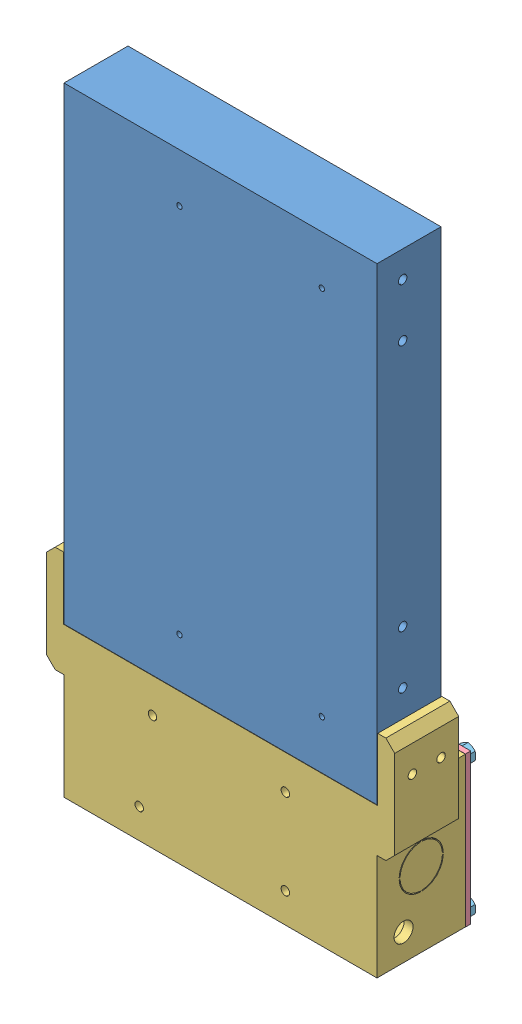
SolidWorks assembly Main, configuration Default. Lengths in mm.
Overall size (200.8 349.9 56.8).
15 component instances, 6 part files, 33 mates.
Components (placement in the parent):
- Box-1: Box [Default] at (0 389.0123 0) x (-1 0 0) z (0 0 -1) size (177 265 36.2)
- Screen Assembly-2: Screen Assembly [Default] at (0 389.0123 -35.1) x (-1 0 0) z (0 0 -1) size (167 255 31.2)
- Box - CTU Addon-1: Box - CTU Addon [Default] at (0 214.2123 0) x (-1 0 0) z (0 0 -1) size (197 120 50)
- Box - Ctu Addon - LID-1: Box - Ctu Addon - LID [Default] at (0 214.0123 -53) x (-1 0 0) z (0 1 0) size (177 3 84.8)
- hex screw_am-2: hex screw_am [B18.6.7M - M5 x 0.8 x 6 Indented HHMS --6N] at (-102.3 271.5123 -26.2) size (9.8 9.24 8)
- hex screw_am-3: hex screw_am [B18.6.7M - M5 x 0.8 x 6 Indented HHMS --6N] at (-102.3 271.5123 -10) size (9.8 9.24 8)
- hex screw_am-4: hex screw_am [B18.6.7M - M5 x 0.8 x 6 Indented HHMS --6N] at (-92.3 306.5123 -14.5) size (9.8 9.24 8)
- hex screw_am-5: hex screw_am [B18.6.7M - M5 x 0.8 x 6 Indented HHMS --6N] at (-92.3 336.5123 -14.5) size (9.8 9.24 8)
- hex screw_am-6: hex screw_am [B18.6.7M - M5 x 0.8 x 6 Indented HHMS --6N] at (-92.3 476.5123 -14.5) size (9.8 9.24 8)
- hex screw_am-7: hex screw_am [B18.6.7M - M5 x 0.8 x 6 Indented HHMS --6N] at (-92.3 506.5123 -14.5) size (9.8 9.24 8)
- hex screw_am-8: hex screw_am [B18.6.7M - M5 x 0.8 x 6 Indented HHMS --6N] at (-83.5 251.7123 -56.8) x (0 0 1) z (-1 0 0) size (9.8 9.24 8)
- hex screw_am-9: hex screw_am [B18.6.7M - M5 x 0.8 x 6 Indented HHMS --6N] at (-83.5 176.7123 -56.8) x (0 0 1) z (-1 0 0) size (9.8 9.24 8)
- hex screw_am-10: hex screw_am [B18.6.7M - M5 x 0.8 x 6 Indented HHMS --6N] at (83.5 176.7123 -56.8) x (0 0 1) z (-1 0 0) size (9.8 9.24 8)
- hex screw_am-11: hex screw_am [B18.6.7M - M5 x 0.8 x 6 Indented HHMS --6N] at (83.5 251.7123 -56.8) x (0 0 1) z (-1 0 0) size (9.8 9.24 8)
- ArduinoMega-1: ArduinoMega [Default] at (0 212.6417 -9.651) size (107.95 53.42 12.95)
Mates (geometry in assembly coordinates):
- Coincident2: coincident anti-aligned: plane of Box-1 through (0 389.0123 -5) normal (0 0 -1); plane of Screen Assembly-2 through (-76.67 509.6823 -5) normal (0 0 1)
- Width1: width aligned: plane of Box-1 through (83.7 261.3123 -36.2) normal (0 1 0); plane of Box-1 through (-83.7 516.7123 -36.2) normal (0 -1 0); plane of Screen Assembly-2 through (76.67 516.5123 -36.2) normal (0 1 0); plane of Screen Assembly-2 through (76.67 261.5123 -36.2) normal (0 -1 0)
- Width2: width anti-aligned: plane of Screen Assembly-2 through (-83.5 268.3423 -36.2) normal (-1 0 0); plane of Screen Assembly-2 through (83.5 268.3423 -36.2) normal (1 0 0); plane of Box-1 through (-83.7 261.3123 -36.2) normal (1 0 0); plane of Box-1 through (83.7 516.7123 -36.2) normal (-1 0 0)
- Width3: width aligned: plane of Box-1 through (-88.5 256.5123 -5) normal (-1 0 0); plane of Box-1 through (88.5 256.5123 -5) normal (1 0 0); plane of Box - CTU Addon-1 through (-88.5 171.7123 -50) normal (-1 0 0); plane of Box - CTU Addon-1 through (88.5 171.7123 -50) normal (1 0 0)
- Coincident4: coincident aligned: plane of Box-1 through (0 389.0123 0) normal (0 0 1); plane of Box - CTU Addon-1 through (0 214.2123 0) normal (0 0 1)
- Distance4: distance = 0.2 mm anti-aligned: plane of Box-1 through (88.5 256.5123 -5) normal (0 -1 0); plane of Box - CTU Addon-1 through (-88.9 256.3123 -50) normal (0 1 0)
- Width4: width aligned: plane of Box - CTU Addon-1 through (88.5 171.7123 -50) normal (0 -1 0); plane of Box - CTU Addon-1 through (-88.9 256.3123 -50) normal (0 1 0); plane of Box - Ctu Addon - LID-1 through (88.5 171.6123 -50) normal (0 -1 0); plane of Box - Ctu Addon - LID-1 through (88.5 256.4123 -50) normal (0 1 0)
- Width5: width aligned: plane of Box - Ctu Addon - LID-1 through (88.5 256.4123 -50) normal (1 0 0); plane of Box - Ctu Addon - LID-1 through (-88.5 256.4123 -50) normal (-1 0 0); plane of Box - CTU Addon-1 through (88.5 171.7123 -50) normal (1 0 0); plane of Box - CTU Addon-1 through (-88.5 171.7123 -50) normal (-1 0 0)
- Coincident6: coincident anti-aligned: plane of Box - CTU Addon-1 through (0 214.2123 -50) normal (0 0 -1); plane of Box - Ctu Addon - LID-1 through (0 214.0123 -50) normal (0 0 1)
- Coincident7: coincident anti-aligned: plane of Box-1 through (0 389.0123 0) normal (-1 0 0)
- Coincident8: coincident anti-aligned: plane of Box-1 through (0 389.0123 0) normal (0 0 -1)
- Concentric9: concentric anti-aligned: cylinder of Box - CTU Addon-1 through (-98.5 271.5123 -26.2) axis (1 0 0) radius 2.4; cylinder of hex screw_am-2 through (-127.7 271.5123 -26.2) axis (-1 0 0) radius 2.5
- Coincident17: coincident anti-aligned: plane of Box - CTU Addon-1 through (-98.5 231.7123 -36.2) normal (-1 0 0); plane of hex screw_am-2 through (-98.5 274.0123 -26.2) normal (1 0 0)
- Concentric10: concentric anti-aligned: cylinder of Box - CTU Addon-1 through (-98.5 271.5123 -10) axis (1 0 0) radius 2.4; cylinder of hex screw_am-3 through (-127.7 271.5123 -10) axis (-1 0 0) radius 2.5
- Coincident18: coincident anti-aligned: plane of Box - CTU Addon-1 through (-98.5 231.7123 -36.2) normal (-1 0 0); plane of hex screw_am-3 through (-98.5 274.0123 -10) normal (1 0 0)
- Concentric11: concentric aligned: cylinder of Box-1 through (95.2882 306.5123 -14.5) axis (-1 0 0) radius 2.4; cylinder of hex screw_am-4 through (-117.7 306.5123 -14.5) axis (-1 0 0) radius 2.5
- Coincident19: coincident anti-aligned: plane of Box-1 through (-88.5 256.5123 -5) normal (-1 0 0); plane of hex screw_am-4 through (-88.5 309.0123 -14.5) normal (1 0 0)
- Concentric12: concentric aligned: cylinder of Box-1 through (95.2882 336.5123 -14.5) axis (-1 0 0) radius 2.4; cylinder of hex screw_am-5 through (-117.7 336.5123 -14.5) axis (-1 0 0) radius 2.5
- Coincident20: coincident anti-aligned: plane of Box-1 through (-88.5 256.5123 -5) normal (-1 0 0); plane of hex screw_am-5 through (-88.5 339.0123 -14.5) normal (1 0 0)
- Concentric13: concentric aligned: cylinder of Box-1 through (95.2882 476.5123 -14.5) axis (-1 0 0) radius 2.4; cylinder of hex screw_am-6 through (-117.7 476.5123 -14.5) axis (-1 0 0) radius 2.5
- Coincident21: coincident anti-aligned: plane of Box-1 through (-88.5 256.5123 -5) normal (-1 0 0); plane of hex screw_am-6 through (-88.5 479.0123 -14.5) normal (1 0 0)
- Concentric14: concentric aligned: cylinder of Box-1 through (95.2882 506.5123 -14.5) axis (-1 0 0) radius 2.4; cylinder of hex screw_am-7 through (-117.7 506.5123 -14.5) axis (-1 0 0) radius 2.5
- Coincident22: coincident anti-aligned: plane of Box-1 through (-88.5 256.5123 -5) normal (-1 0 0); plane of hex screw_am-7 through (-88.5 509.0123 -14.5) normal (1 0 0)
- Concentric15: concentric anti-aligned: cylinder of Box - Ctu Addon - LID-1 through (-83.5 251.7123 -53) axis (0 0 1) radius 1.6; cylinder of hex screw_am-8 through (-83.5 251.7123 -82.2) axis (0 0 -1) radius 2.5
- Coincident23: coincident anti-aligned: plane of Box - Ctu Addon - LID-1 through (0 214.0123 -53) normal (0 0 -1); plane of hex screw_am-8 through (-83.5 254.2123 -53) normal (0 0 1)
- Concentric16: concentric anti-aligned: cylinder of Box - Ctu Addon - LID-1 through (-83.5 176.7123 -53) axis (0 0 1) radius 1.6; cylinder of hex screw_am-9 through (-83.5 176.7123 -82.2) axis (0 0 -1) radius 2.5
- Coincident24: coincident anti-aligned: plane of Box - Ctu Addon - LID-1 through (0 214.0123 -53) normal (0 0 -1); plane of hex screw_am-9 through (-83.5 179.2123 -53) normal (0 0 1)
- Concentric17: concentric anti-aligned: cylinder of Box - Ctu Addon - LID-1 through (83.5 176.7123 -53) axis (0 0 1) radius 1.6; cylinder of hex screw_am-10 through (83.5 176.7123 -82.2) axis (0 0 -1) radius 2.5
- Coincident25: coincident anti-aligned: plane of Box - Ctu Addon - LID-1 through (0 214.0123 -53) normal (0 0 -1); plane of hex screw_am-10 through (83.5 179.2123 -53) normal (0 0 1)
- Concentric18: concentric anti-aligned: cylinder of Box - Ctu Addon - LID-1 through (83.5 251.7123 -53) axis (0 0 1) radius 1.6; cylinder of hex screw_am-11 through (83.5 251.7123 -82.2) axis (0 0 -1) radius 2.5
- Coincident26: coincident anti-aligned: plane of Box - Ctu Addon - LID-1 through (0 214.0123 -53) normal (0 0 -1); plane of hex screw_am-11 through (83.5 254.2123 -53) normal (0 0 1)
- Distance5: distance = 3 mm anti-aligned: plane of Box - CTU Addon-1 through (0 214.2123 -5) normal (0 0 -1); plane of ArduinoMega-1 through (50.8 185.9336 -8) normal (0 0 1)
- Width6: width aligned: plane of Box - CTU Addon-1 through (-83.5 171.7123 -50) normal (1 0 0); plane of ArduinoMega-1 through (83.5 171.7123 -50) normal (-1 0 0); plane of Box - CTU Addon-1 through (50.8 239.3498 -8) normal (1 0 0); plane of ArduinoMega-1 through (-50.8 239.3498 -8) normal (-1 0 0)
